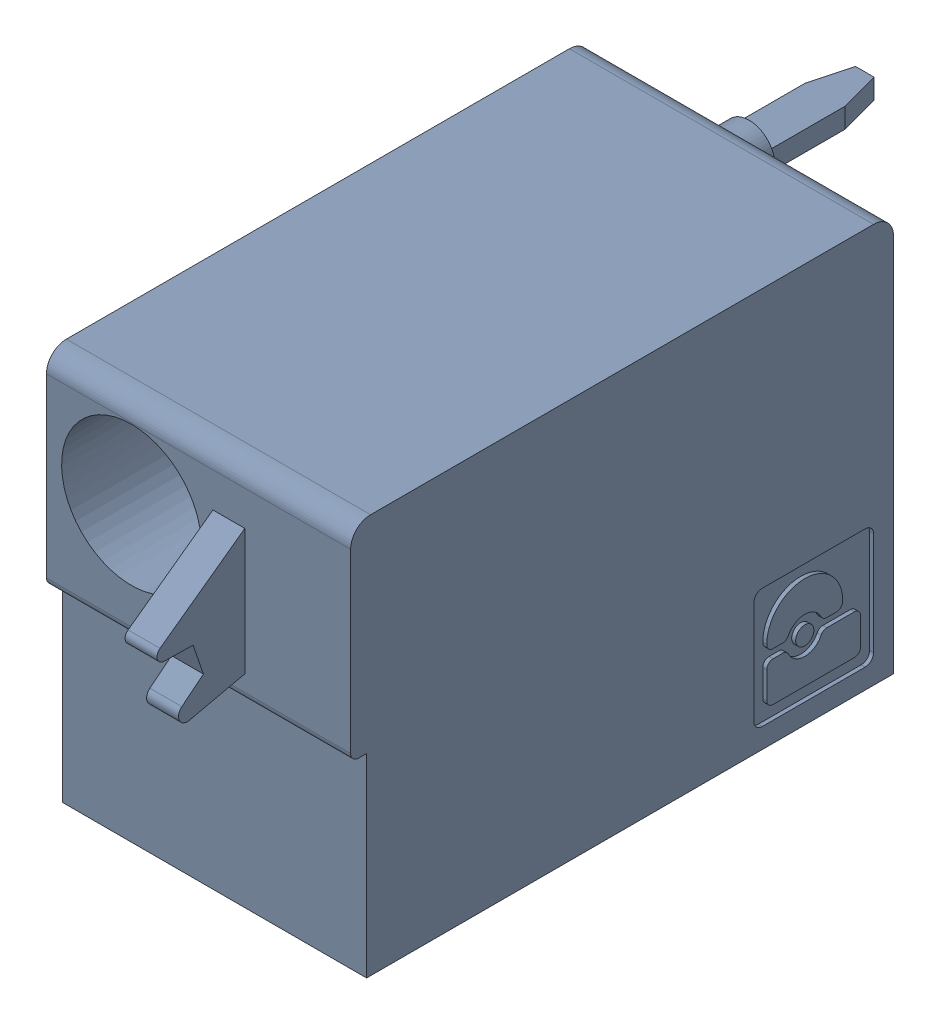
SolidWorks assembly J52, configuration Default. Lengths in mm.
Overall size (7.62 10 19.2).
2 component instances, 1 part files, 0 mates.
Components (placement in the parent):
- 1790487-1: 1790487 [Default] at (137.565 -15.67 -10.6) x (0 1 0) z (1 0 0) size (10 19.2 7.62)
  - ffkdsa1-v2-7.62-1: ffkdsa1-v2-7.62 [Default] at (-15.6914 -27.508 9.12) x (0 -1 0) z (0 0 1) size (19.2 10 7.62)
